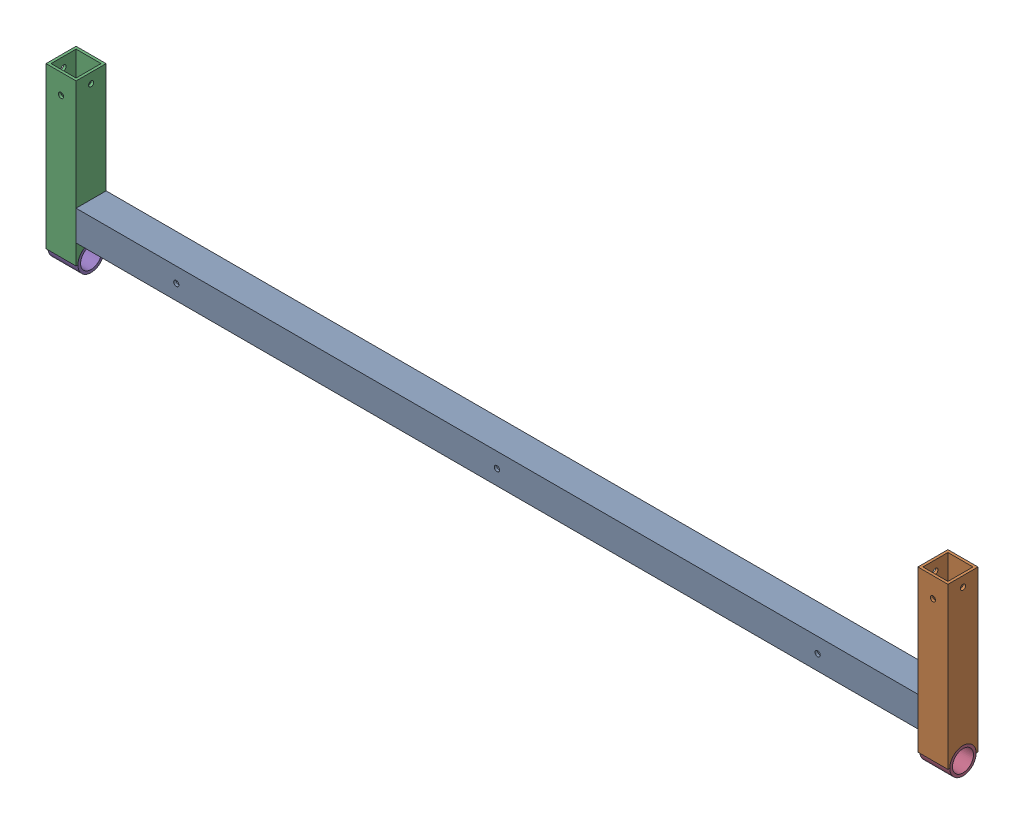
SolidWorks assembly GE-16171_ASM, configuration Default. Lengths in mm.
Overall size (1143 219.9 38.1).
5 component instances, 3 part files, 0 mates.
Components (placement in the parent):
- GE-16171-01-1: GE-16171-01 [Default] at origin size (1066.8 38.1 38.1)
- GE-16171-02-1: GE-16171-02 [Default] at (552.45 57.15 0) x (1 0 0) z (0 1 0) size (38.1 38.1 203.2)
- GE-16171-02-2: GE-16171-02 [Default] at (-552.45 57.15 0) x (1 0 0) z (0 1 0) size (38.1 38.1 203.2)
- GE-16171-03-1: GE-16171-03 [Default] at (552.45 -44.45 0) x (0 -1 0) z (0 0 1) size (33.4 38.1 33.4)
- GE-16171-03-2: GE-16171-03 [Default] at (-552.45 -44.45 0) x (0 -1 0) z (0 0 1) size (33.4 38.1 33.4)
